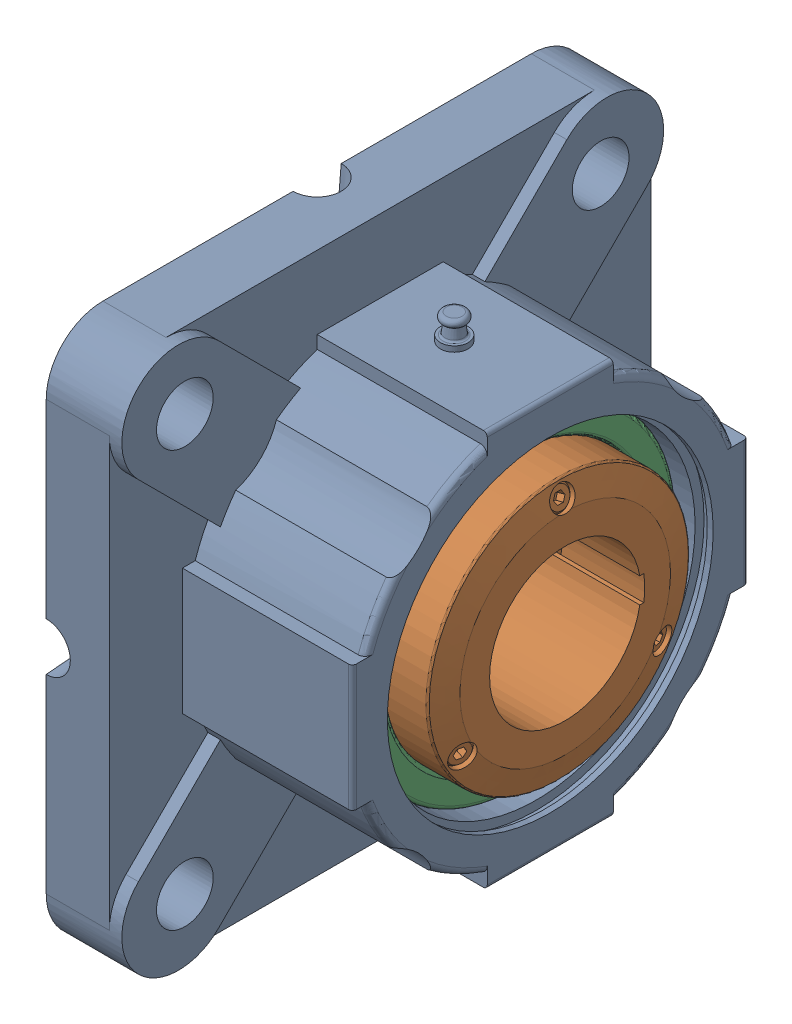
SolidWorks assembly SKF_F4BE 108-SRB-CRE, configuration Default. Lengths in mm.
Overall size (64.7 148.17 148.17).
4 component instances, 3 part files, 0 mates.
Components (placement in the parent):
- SKF_F4BE 108-SRB-CRE_h-1: SKF_F4BE 108-SRB-CRE_h [Default] at origin size (58.75 136.53 136.53)
- ABSY 22208-108_b-1: ABSY 22208-108_b [Default] at (30.163 0 0) size (64.7 80 80)
- SKF_F4BE 108-SRB-CRE_seal-1: SKF_F4BE 108-SRB-CRE_seal [Default] at (45.633 0 0) size (5 80 80)
- SKF_F4BE 108-SRB-CRE_seal-2: SKF_F4BE 108-SRB-CRE_seal [Default] at (9.693 0 0) size (5 80 80)
